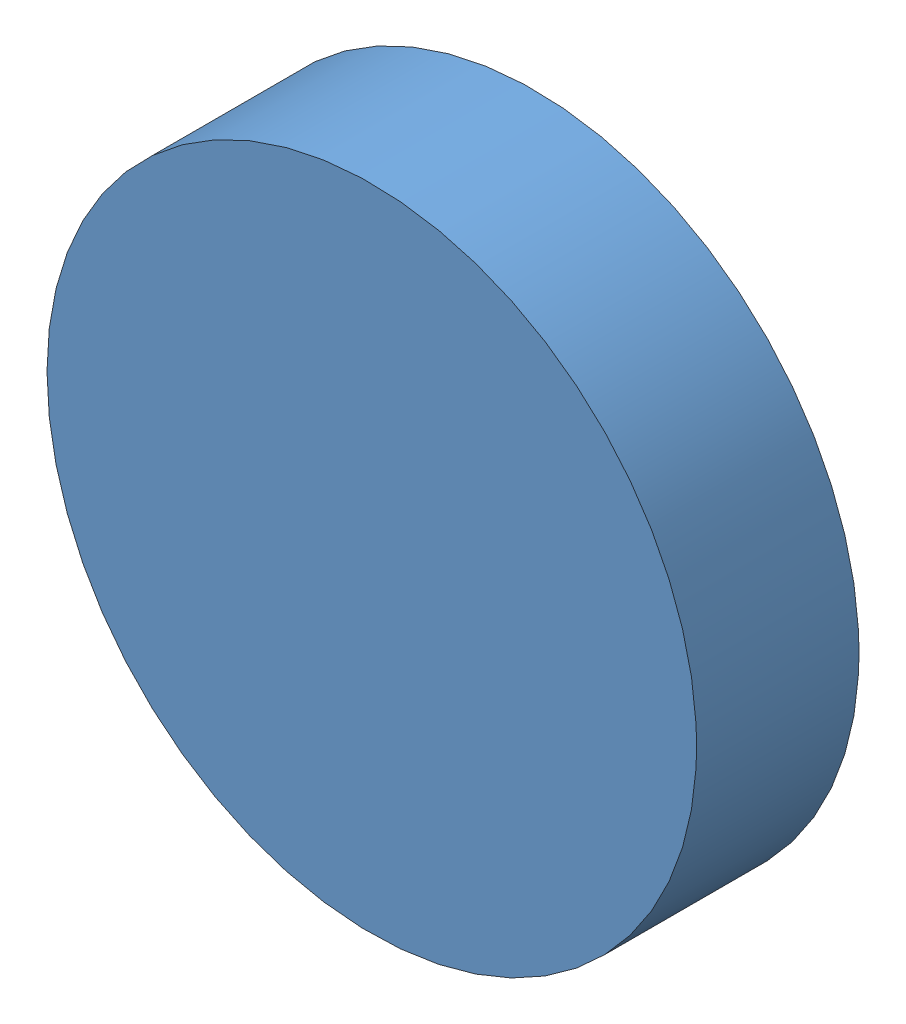
SolidWorks assembly MOULE, configuration Défaut. Lengths in mm.
Overall size (101.34 101.34 65).
3 component instances, 3 part files, 4 mates.
Components (placement in the parent):
- MOULE 1-1: MOULE 1 [Défaut] at (-5.5608 3.3128 100) size (100 100 25)
- PORTE MANTEAU-1: PORTE MANTEAU [Défaut] at (-5.5608 3.3128 95) x (-0.923728 -0.383049 0) z (0 0 -1) size (50 50 40) (hidden)
- MOULE 2-2: MOULE 2 [Défaut] at (-5.5608 3.3128 110) x (0.99991 -0.013442 0) z (0 0 1) size (100 100 40)
Mates (geometry in assembly coordinates):
- Coïncidente1: coincident aligned: plane of MOULE 1-1 through (-5.5608 3.3128 110) normal (0 0 1); plane of PORTE MANTEAU-1 through (-5.5608 3.3128 110) normal (0 0 1)
- Coaxiale1: concentric anti-aligned: cylinder of MOULE 1-1 through (-5.5608 3.3128 110) axis (0 0 -1) radius 50; circle of PORTE MANTEAU-1
- Coïncidente3: coincident anti-aligned: plane of MOULE 1-1 through (-5.5608 3.3128 110) normal (0 0 1); plane of MOULE 2-2 through (-5.5608 3.3128 110) normal (0 0 -1)
- Coaxiale2: concentric aligned: cylinder of MOULE 1-1 through (-5.5608 3.3128 110) axis (0 0 -1) radius 50; cylinder of MOULE 2-2 through (-5.5608 3.3128 150) axis (0 0 -1) radius 50
